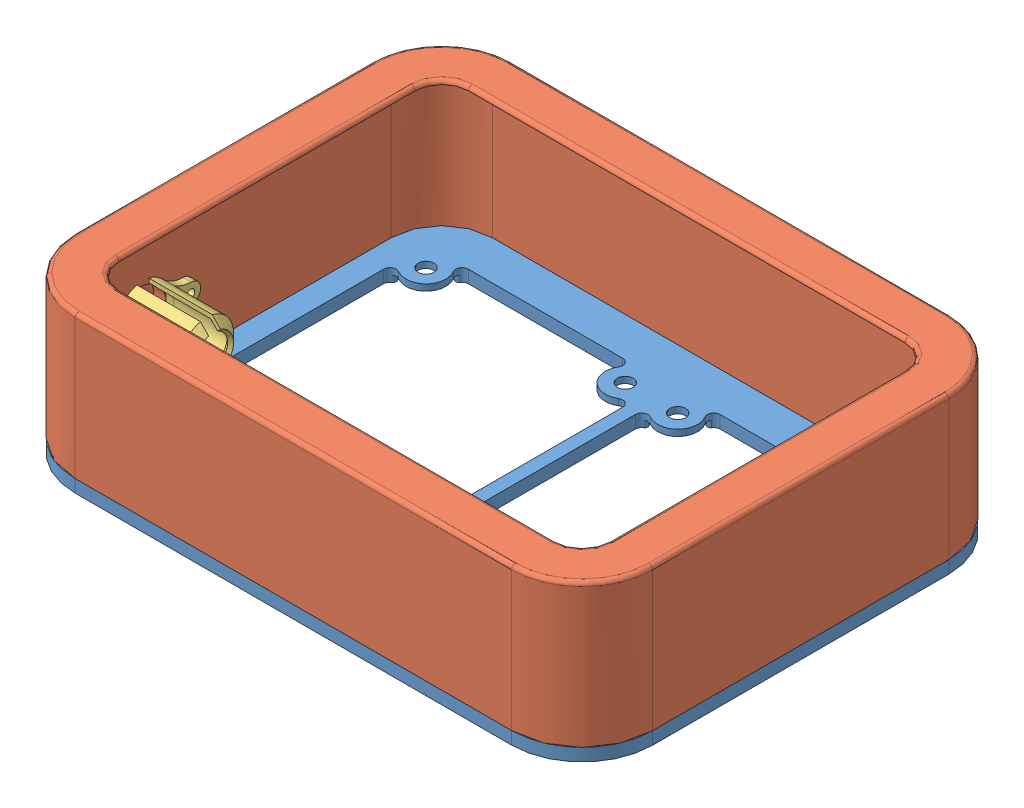
SolidWorks assembly Solder Fan, configuration Default. Lengths in mm.
Overall size (144.94 39.1 109.7).
3 component instances, 3 part files, 4 mates.
Components (placement in the parent):
- Fan Backplate-1: Fan Backplate [Default] at origin size (144.94 4.76 109.7)
- Over Shroud-1: Over Shroud [Default] at (0 38.1 10) x (0 -1 0) z (-1 0 0) size (35.92 109.7 144.94)
- Part1^Solder Fan-1: Part1^Solder Fan [Default] at origin size (17.99 13.43 25) (virtual)
Mates (geometry in assembly coordinates):
- Coincident1: coincident anti-aligned: plane of Over Shroud-1 through (0 38.1 10) normal (-1 0 0)
- Parallel1: parallel anti-aligned: plane of Over Shroud-1 through (0 38.1 10) normal (0 -1 0)
- Distance1: distance = 10 mm aligned: plane of Over Shroud-1 through (0 38.1 10) normal (0 0 1)
- Coincident4: coincident anti-aligned: plane of Fan Backplate-1 through (0 3.175 0) normal (0 1 0); plane of Over Shroud-1 through (-54.7687 3.175 47.1475) normal (0 -1 0)
